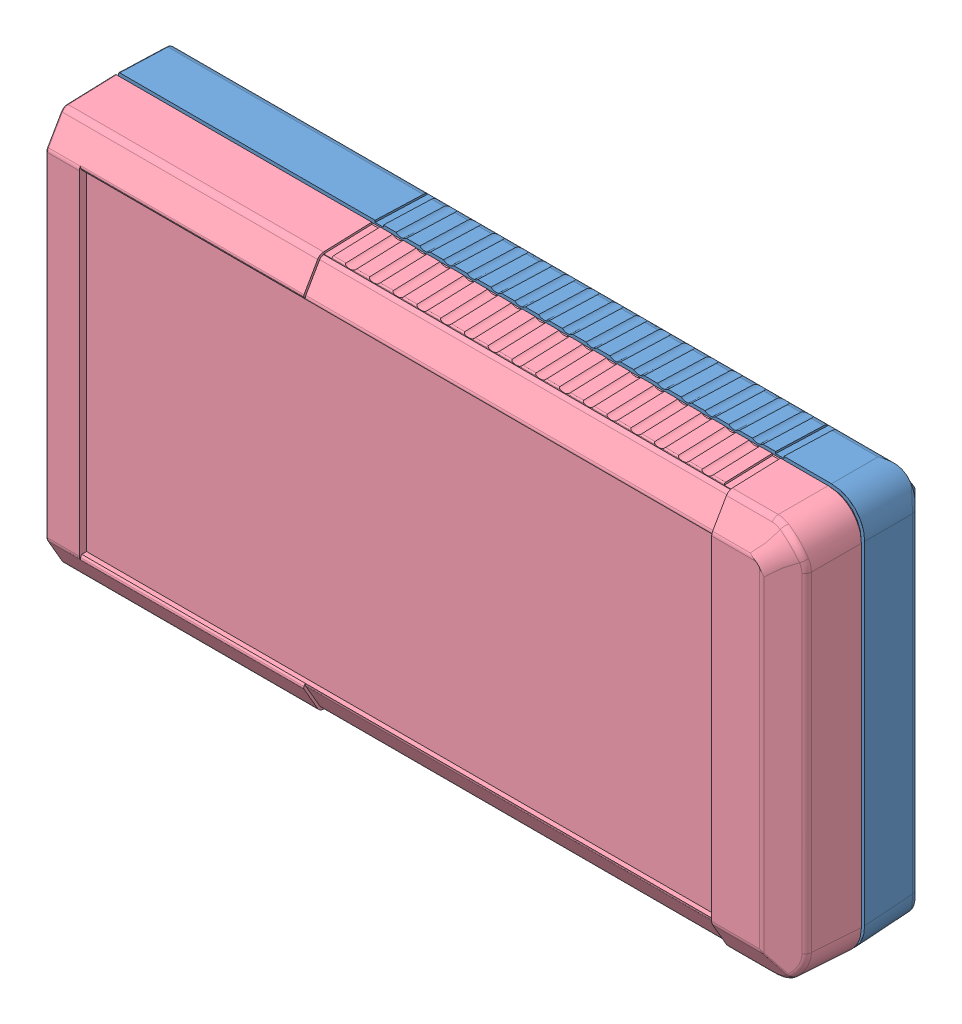
SolidWorks assembly BOS-761, configuration Mantra. Lengths in mm.
Overall size (157.4 85.35 31.24).
4 component instances, 4 part files, 9 mates.
Components (placement in the parent):
- BottomShell-1: BottomShell [Domyślna] at (-299.4823 -8.6835 175.1914)
- FrontCover-1: FrontCover [Domyślna] at (-54.0319 42.8028 198.1424) x (0 -1 0) z (-1 0 0)
- SwitchSlide-1: SwitchSlide [Domyślna] at (10.3405 -28.5467 190.4914) x (-1 0 0) z (0 0 1)
- TopShell-1: TopShell [Mantra] at (-299.4823 42.6775 204.8914) x (1 0 0) z (0 0 -1) size (157 84 17.54)
Mates (geometry in assembly coordinates):
- Coincident5: coincident anti-aligned: plane of BottomShell-1 through (-54.0319 52.0951 176.6914) normal (0 0 1); plane of FrontCover-1 through (-54.0319 52.1592 176.6914) normal (0 0 -1)
- Coincident3: coincident anti-aligned: plane of BottomShell-1 through (-54.0319 57.497 189.6914) normal (0 -0.999391 0.034899); plane of FrontCover-1 through (-54.0319 57.5092 190.0414) normal (0 0.999391 -0.034899)
- Coincident4: coincident anti-aligned: plane of BottomShell-1 through (-54.0319 -8.6835 175.1914) normal (-1 0 0); plane of FrontCover-1 through (-54.0319 42.8028 198.1424) normal (1 0 0)
- Concentric5: concentric anti-aligned: cylinder of BottomShell-1 through (-49.0319 48.497 189.6914) axis (0 0 -1) radius 3; cylinder of TopShell-1 through (-49.0319 48.497 189.3914) axis (0 0 1) radius 3
- Concentric6: concentric anti-aligned: cylinder of BottomShell-1 through (-49.0319 -14.503 189.6914) axis (0 0 -1) radius 3; cylinder of TopShell-1 through (-49.0319 -14.503 189.3914) axis (0 0 1) radius 3
- Coincident10: coincident anti-aligned: plane of FrontCover-1 through (-54.0319 -17.8408 203.3914) normal (0 0 1); plane of TopShell-1 through (-299.4823 42.6775 203.3914) normal (0 0 -1)
- Coincident11: coincident anti-aligned: plane of SwitchSlide-1 through (0.8681 -24.753 196.4914) normal (0 0 1); plane of TopShell-1 through (23.5681 -23.653 196.4914) normal (0 0 -1)
- Coincident12: coincident anti-aligned: plane of SwitchSlide-1 through (18.3681 -22.003 197.9914) normal (0 -1 0); plane of TopShell-1 through (95.4681 -22.003 202.3914) normal (0 1 0)
- Width1: width anti-aligned: plane of TopShell-1 through (23.5681 42.6775 204.8914) normal (-1 0 0); plane of TopShell-1 through (8.3681 42.6775 204.8914) normal (1 0 0); plane of SwitchSlide-1 through (18.3681 -20.053 189.6414) normal (1 0 0); plane of SwitchSlide-1 through (8.3681 -20.053 196.4914) normal (-1 0 0)
